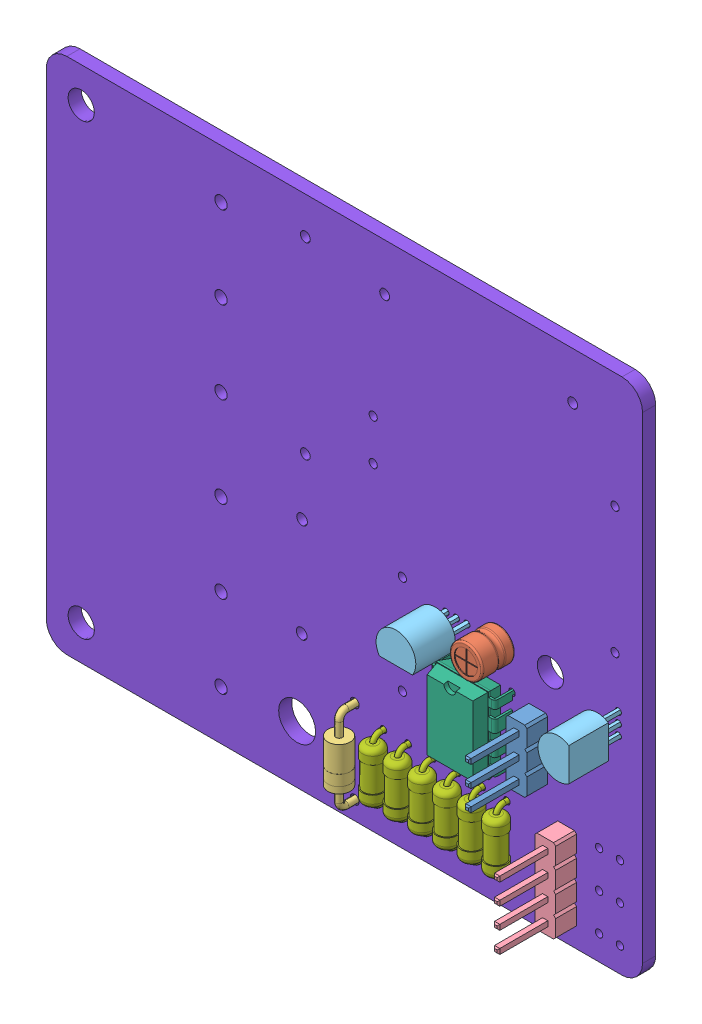
SolidWorks assembly PCB, configuration Default. Lengths in mm.
Overall size (72.5 63 11.84).
30 component instances, 8 part files, 0 mates.
Components (placement in the parent):
- PinHeader_1x03_P2.54mm_Vertical-1: PinHeader_1x03_P2.54mm_Vertical [Default] at (168 -113.75 1.65) size (2.54 7.62 11.54)
  - SOLID-1: SOLID [Default] at origin size (2.54 7.62 11.54)
- CP_Radial_D4.0mm_P1.50mm-1: CP_Radial_D4.0mm_P1.50mm [Default] at (162.56 -107.95 1.65) size (4.92 5.21 6)
  - SOLID_2-1: SOLID_2 [Default] at origin size (4.92 5.21 6)
- D_DO-41_SOD81_P10.16mm_Horizontal-1: D_DO-41_SOD81_P10.16mm_Horizontal [Default] at (145.75 -133.25 1.65) x (0 1 0) z (0 0 1) size (10.96 2.72 5.71)
  - SOLID_3-1: SOLID_3 [Default] at origin size (10.96 2.72 5.71)
- LED_D3.0mm-1: LED_D3.0mm [Default] at (178 -123.5 1.65) x (-1 0 0) z (0 0 1) (suppressed, hidden)
- LED_D3.0mm-2: LED_D3.0mm [Default] at (178 -128 1.65) x (-1 0 0) z (0 0 1) (suppressed, hidden)
- LED_D3.0mm-3: LED_D3.0mm [Default] at (178 -132.5 1.65) x (-1 0 0) z (0 0 1) (suppressed, hidden)
- PinHeader_1x04_P2.54mm_Vertical-1: PinHeader_1x04_P2.54mm_Vertical [Default] at (171.5 -132 1.65) x (-1 0 0) z (0 0 1) size (2.54 10.16 11.54)
  - SOLID_5-1: SOLID_5 [Default] at origin size (2.54 10.16 11.54)
- TO-92_Inline-1: TO-92_Inline [Default] at (156.845 -107.95 1.65) size (4.83 3.75 9.8)
  - SOLID_6-1: SOLID_6 [Default] at origin size (4.83 3.75 9.8)
- TO-92_Inline-2: TO-92_Inline [Default] at (177.8 -110.49 1.65) x (0 1 0) z (0 0 1) size (4.83 3.75 9.8)
  - SOLID_6-1: SOLID_6 [Default] at origin size (4.83 3.75 9.8)
- DIP-8_W7.62mm-1: DIP-8_W7.62mm [Default] at (157.25 -112.395 1.65) size (7.87 9.27 6.98)
  - SOLID_7-1: SOLID_7 [Default] at origin size (7.87 9.27 6.98)
- R_Axial_DIN0207_L6.3mm_D2.5mm_P7.62mm_Horizontal-1: R_Axial_DIN0207_L6.3mm_D2.5mm_P7.62mm_Horizontal [Default] at (149.25 -131.75 1.65) x (0 1 0) z (0 0 1) size (8.22 2.5 5.5)
  - SOLID_8-1: SOLID_8 [Default] at origin size (8.22 2.5 5.5)
- R_Axial_DIN0207_L6.3mm_D2.5mm_P7.62mm_Horizontal-2: R_Axial_DIN0207_L6.3mm_D2.5mm_P7.62mm_Horizontal [Default] at (161.25 -124.13 1.65) x (0 -1 0) z (0 0 1) size (8.22 2.5 5.5)
  - SOLID_8-1: SOLID_8 [Default] at origin size (8.22 2.5 5.5)
- R_Axial_DIN0207_L6.3mm_D2.5mm_P7.62mm_Horizontal-3: R_Axial_DIN0207_L6.3mm_D2.5mm_P7.62mm_Horizontal [Default] at (158.25 -131.75 1.65) x (0 1 0) z (0 0 1) size (8.22 2.5 5.5)
  - SOLID_8-1: SOLID_8 [Default] at origin size (8.22 2.5 5.5)
- R_Axial_DIN0207_L6.3mm_D2.5mm_P7.62mm_Horizontal-4: R_Axial_DIN0207_L6.3mm_D2.5mm_P7.62mm_Horizontal [Default] at (155.25 -131.75 1.65) x (0 1 0) z (0 0 1) size (8.22 2.5 5.5)
  - SOLID_8-1: SOLID_8 [Default] at origin size (8.22 2.5 5.5)
- R_Axial_DIN0207_L6.3mm_D2.5mm_P7.62mm_Horizontal-5: R_Axial_DIN0207_L6.3mm_D2.5mm_P7.62mm_Horizontal [Default] at (152.25 -131.75 1.65) x (0 1 0) z (0 0 1) size (8.22 2.5 5.5)
  - SOLID_8-1: SOLID_8 [Default] at origin size (8.22 2.5 5.5)
- R_Axial_DIN0207_L6.3mm_D2.5mm_P7.62mm_Horizontal-6: R_Axial_DIN0207_L6.3mm_D2.5mm_P7.62mm_Horizontal [Default] at (164.25 -131.75 1.65) x (0 1 0) z (0 0 1) size (8.22 2.5 5.5)
  - SOLID_8-1: SOLID_8 [Default] at origin size (8.22 2.5 5.5)
- COMPOUND-1: COMPOUND [Default] at origin size (72.5 63 1.6)
